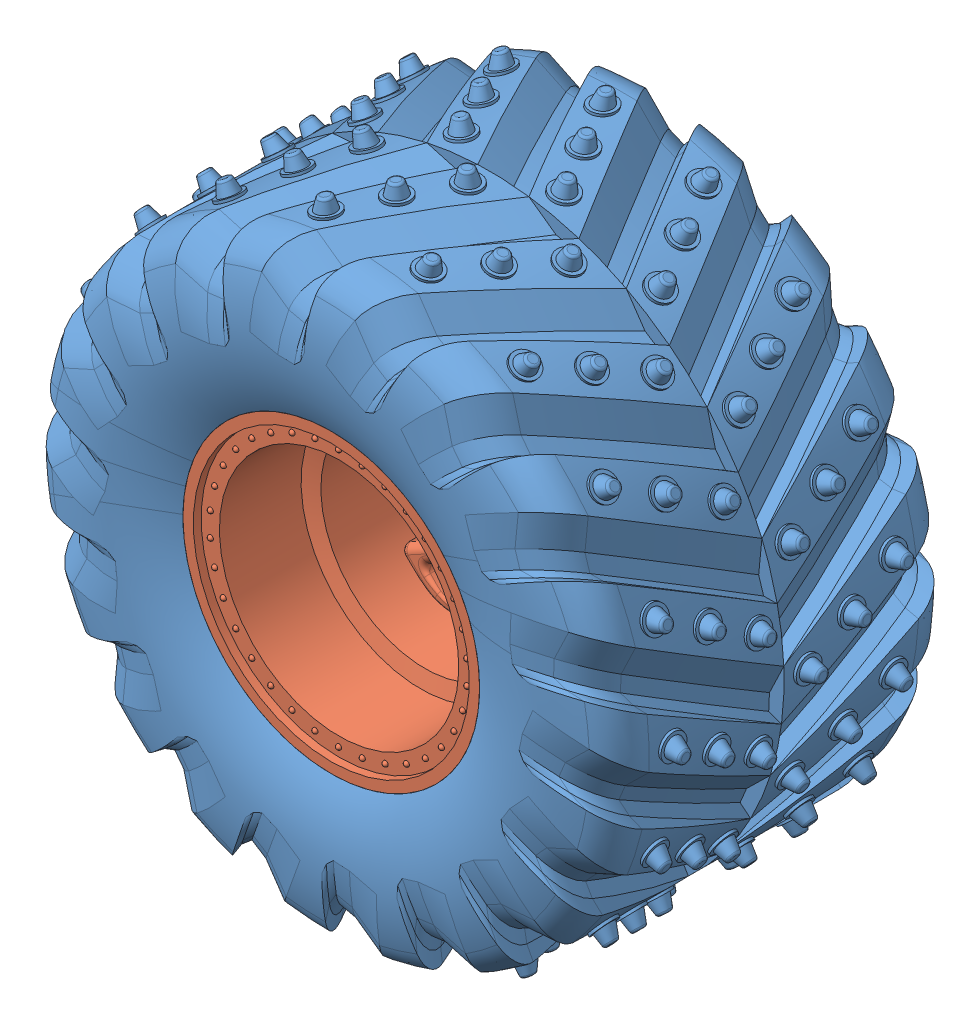
SolidWorks assembly Wheel, configuration Default. Lengths in mm.
Overall size (118.99 118.99 72.77).
2 component instances, 2 part files, 6 mates.
Components (placement in the parent):
- Tyre-1: Tyre [Default] at (0 0 -30.5) size (118.99 118.99 72.77)
- Rim-1: Rim [Default] x (-1 0 0) z (0 0 -1) size (57 57 61)
Mates (geometry in assembly coordinates):
- Coincident1: coincident anti-aligned: plane of Rim-1 through (0 0 0) normal (0 0 -1); plane of assembly through (0 0 0) normal (0 0 1)
- Coincident2: coincident aligned: plane of Rim-1; plane of assembly through (0 0 0) normal (0 1 0)
- Coincident3: coincident anti-aligned: plane of Rim-1 through (0 0 0) normal (-1 0 0); plane of assembly through (0 0 0) normal (1 0 0)
- Concentric1: concentric aligned: cylinder of Tyre-1 through (0 0 -30.5) axis (0 0 1) radius 48.5; cylinder of Rim-1 through (0 0 0) axis (0 0 1) radius 22
- Coincident4: coincident anti-aligned: plane of Tyre-1 through (0 28.5 -3.5) normal (0 0 1); plane of Rim-1 through (0 25 -3.5) normal (0 0 -1)
- Coincident5: coincident aligned: plane of Tyre-1 through (0 0 -30.5) normal (0 1 0); plane of Rim-1
